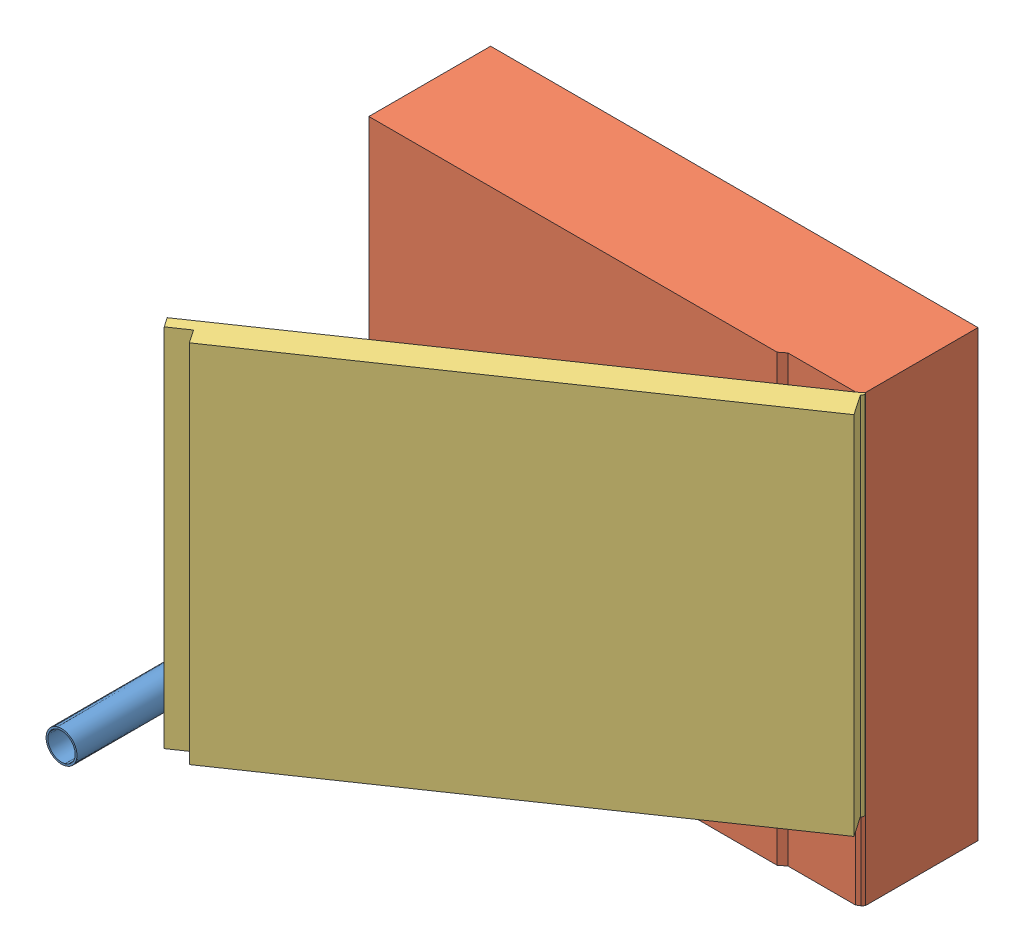
SolidWorks assembly БалкД, configuration По умолчанию. Lengths in mm.
Overall size (826.83 730 800).
3 component instances, 3 part files, 5 mates.
Components (placement in the parent):
- Перила-1: Перила [По умолчанию] at (407.5326 494.8566 909.0671) x (1 0 0) z (0 1 0) size (51 600 51)
- Стена-1: Стена [По умолчанию] at (312.4 313.4846 309.0671) size (800.63 730 200)
- Дверь-1: Дверь [По умолчанию] at (1109.6884 443.4846 297.7675) x (-0.82519 0 0.564855) z (-0.564855 0 -0.82519) size (825 600 50)
Mates (geometry in assembly coordinates):
- Совпадение2: coincident anti-aligned: plane of Перила-1 through (407.5326 494.8566 309.0671) normal (0 0 -1); plane of Стена-1 through (312.4 1043.4846 309.0671) normal (0 0 1)
- Расстояние1: distance = 680 mm aligned: plane of Стена-1 through (1113.0326 1043.4846 109.0671) normal (1 0 0); cylinder of Перила-1 through (407.5326 494.8566 309.0671) axis (0 0 1) radius 25.5
- Концентричный3: concentric aligned: line of Стена-1 through (1109.6884 1043.4846 297.7675) axis (0 -1 0); cylinder of Дверь-1 through (1109.6884 1043.4846 297.7675) axis (0 -1 0) radius 5
- Совпадение5: coincident aligned: plane of Стена-1 through (312.4 1043.4846 309.0671) normal (0 1 0); plane of Дверь-1 through (1109.6884 1043.4846 297.7675) normal (0 1 0)
- Касательность5: tangent: cylinder of Перила-1 through (407.5326 494.8566 309.0671) axis (0 0 1) radius 25.5; line of Дверь-1 through (433.0326 1043.4846 760.9487) axis (0 -1 0)
